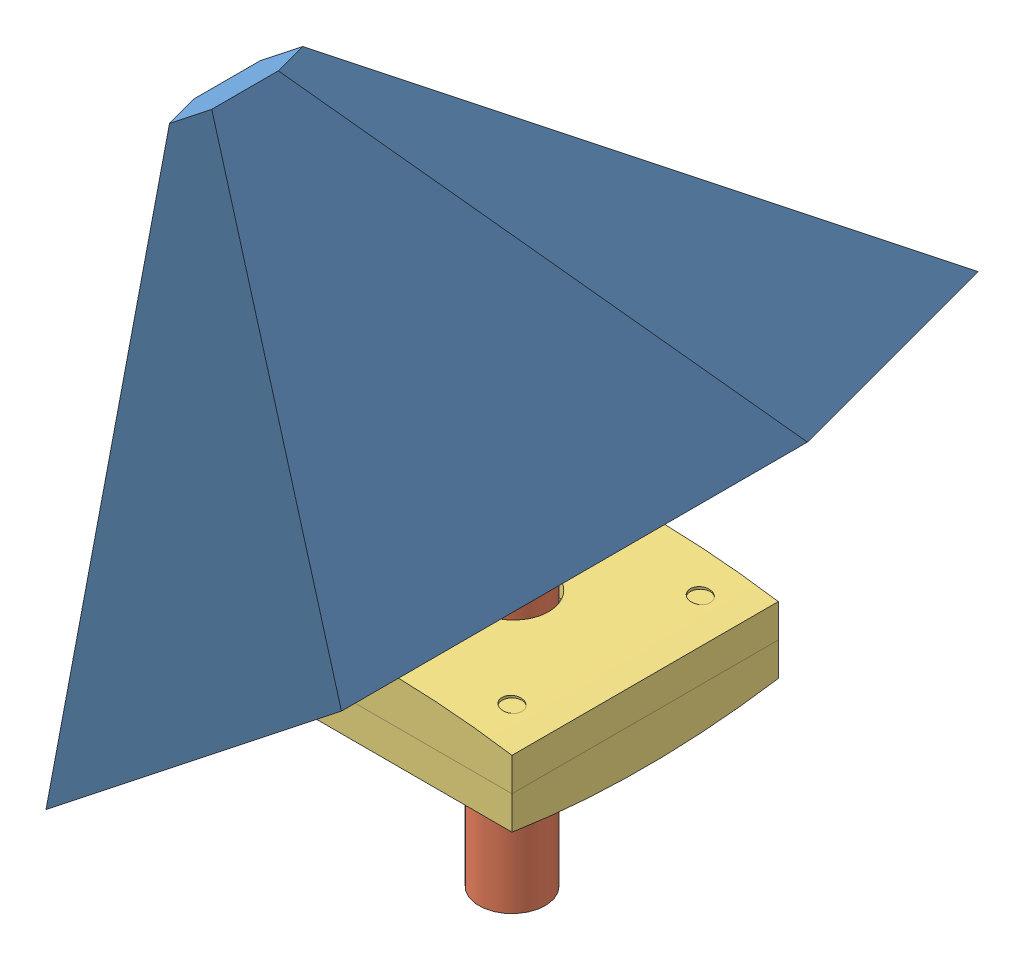
SolidWorks assembly canard_assemb, configuration Default. Lengths in mm.
Overall size (40 125 140).
23 component instances, 9 part files, 0 mates.
Components (placement in the parent):
- canard-1: canard [Default] at (-49.5873 -30.7912 -70) x (-1 0 0) z (0 0 -1) size (18.76 80 140)
- GEARBOX_SHAFT3-1: GEARBOX_SHAFT3 [Default] at (-49.5873 -75.7912 0) x (0 0 -1) z (0 1 0) size (10 10 65)
- shift_fixed_socket-1: shift_fixed_socket [Default] at (-49.5873 -167.1812 -20) x (0 -1 0) z (-1 0 0) size (6.55 40 40)
- 6000DDU-1: 6000DDU [Default] at (-49.5873 -47.7289 0) x (0 1 0) z (0 0 -1) size (8 26 26)
  - 6000DDU Outer ring-1: 6000DDU Outer ring [Default] at origin size (8 26 26)
  - 6000DDU Inner ring-1: 6000DDU Inner ring [Default] x (1 0 0) z (0 1 0) size (8 14.57 14.57)
  - 6000DDU Ball-1: 6000DDU Ball [Default] at (4 0 -9) x (1 0 0) z (0 1 0) size (4 4 4)
  - 6000DDU Ball-2: 6000DDU Ball [Default] at (4 4.1825 -7.9691) x (1 0 0) z (0 1 0) size (4 4 4)
  - 6000DDU Ball-3: 6000DDU Ball [Default] at (4 7.4069 -5.1126) x (1 0 0) z (0 1 0) size (4 4 4)
  - 6000DDU Ball-4: 6000DDU Ball [Default] at (4 8.9344 -1.0848) x (1 0 0) z (0 1 0) size (4 4 4)
  - 6000DDU Ball-5: 6000DDU Ball [Default] at (4 8.4151 3.1914) x (1 0 0) z (0 1 0) size (4 4 4)
  - 6000DDU Ball-6: 6000DDU Ball [Default] at (4 5.9681 6.7366) x (1 0 0) z (0 1 0) size (4 4 4)
  - 6000DDU Ball-7: 6000DDU Ball [Default] at (4 2.1538 8.7385) x (1 0 0) z (0 1 0) size (4 4 4)
  - 6000DDU Ball-8: 6000DDU Ball [Default] at (4 -2.1538 8.7385) x (1 0 0) z (0 1 0) size (4 4 4)
  - 6000DDU Ball-9: 6000DDU Ball [Default] at (4 -5.9681 6.7366) x (1 0 0) z (0 1 0) size (4 4 4)
  - 6000DDU Ball-10: 6000DDU Ball [Default] at (4 -8.4151 3.1914) x (1 0 0) z (0 1 0) size (4 4 4)
  - 6000DDU Ball-11: 6000DDU Ball [Default] at (4 -8.9344 -1.0848) x (1 0 0) z (0 1 0) size (4 4 4)
  - 6000DDU Ball-12: 6000DDU Ball [Default] at (4 -7.4069 -5.1126) x (1 0 0) z (0 1 0) size (4 4 4)
  - 6000DDU Ball-13: 6000DDU Ball [Default] at (4 -4.1825 -7.9691) x (1 0 0) z (0 1 0) size (4 4 4)
  - 6000DDU Shield1-1: 6000DDU Shield1 [Default] at (7.632 0 0) size (0.28 23 23)
  - 6000DDU Shield2-1: 6000DDU Shield2 [Default] at (0.368 0 0) x (-1 0 0) z (0 0 1) size (0.28 23 23)
- shift_fixed_socket-2: shift_fixed_socket [Default] at (-69.5873 79.7234 0) x (0 1 0) z (0 0 -1) size (6.55 40 40)
- FBB4-6-1: FBB4-6 [Default] at (-59.1373 -15.7912 0) x (1 0 0) z (0 -0.191837 -0.981427) size (6 7.86 7.86)
